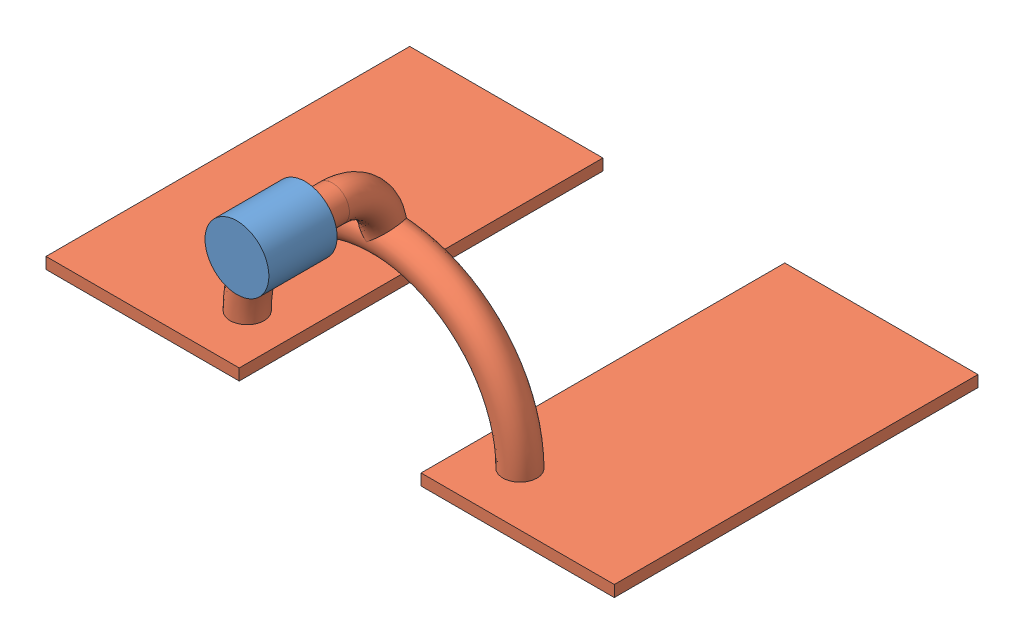
SolidWorks assembly Full_Restrictor, configuration Default. Lengths in mm.
Overall size (25 10.16 20.1).
2 component instances, 2 part files, 6 mates.
Components (placement in the parent):
- Lid_Restrictor-1: Lid_Restrictor [Default] at (0 8.5 10.1) x (1 0 0) z (0 0 -1) size (2.81 2.81 3)
- Restrictor-1: Restrictor [Default] at origin size (25 9.5 19.9)
Mates (geometry in assembly coordinates):
- Coincident1: coincident aligned: plane of assembly; plane of Restrictor-1 through (0 0 0) normal (1 0 0)
- Coincident2: coincident aligned: plane of Restrictor-1 through (0 0 0) normal (0 1 0)
- Coincident3: coincident aligned: plane of Restrictor-1 through (0 0 0) normal (0 0 1)
- Coincident5: coincident aligned: plane of Lid_Restrictor-1 through (0 8.5 23.1557) normal (1 0 0)
- Concentric1: concentric aligned: circle of Lid_Restrictor-1; cylinder of Restrictor-1 through (0 8.5 9.9) axis (0 0 -1) radius 0.75
- Coincident6: coincident anti-aligned: plane of Lid_Restrictor-1 through (0 8.5 9.9) normal (0 0 -1); plane of Restrictor-1 through (0 8.5 9.9) normal (0 0 1)
